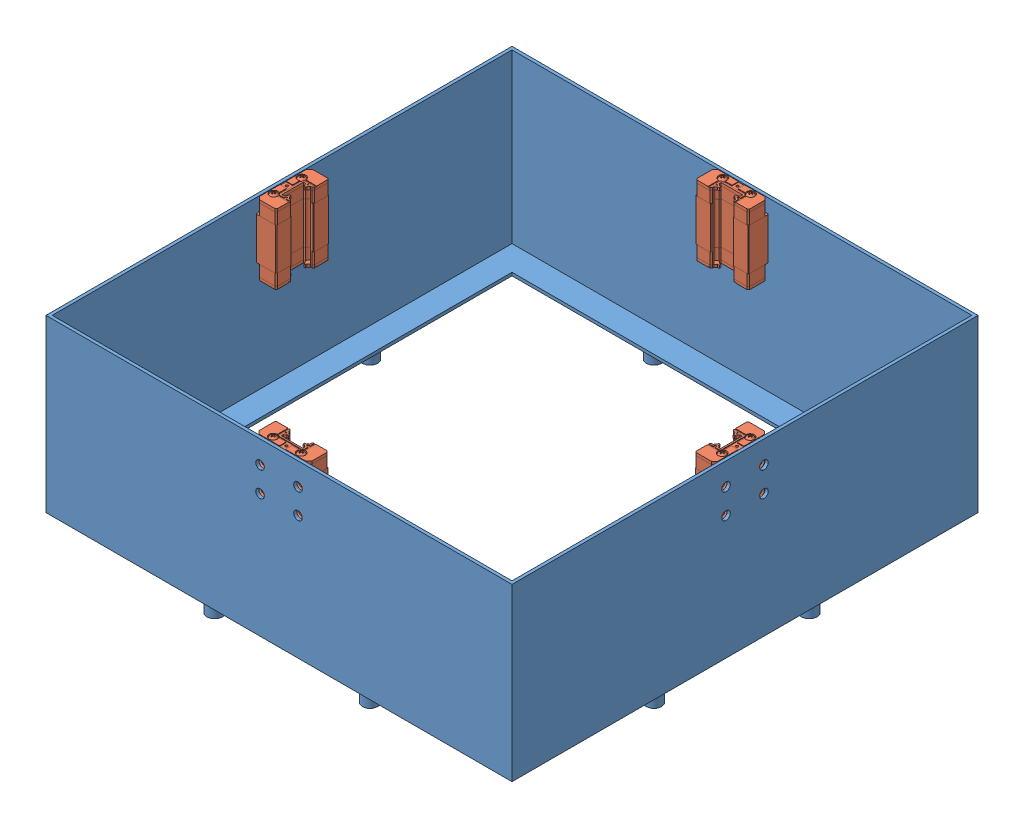
SolidWorks assembly rails boxes, configuration Default. Lengths in mm.
Overall size (150 60.41 150).
5 component instances, 2 part files, 12 mates.
Components (placement in the parent):
- rails-1: rails [Default] at (22.0962 113.7843 129.2829) size (150 60 150)
- MGN7C-1: MGN7C [MGN7C] at (21.9962 102.5343 200.0329) x (-1 0 0) z (0 1 0) size (17 6.5 23.31)
- MGN7C-2: MGN7C [MGN7C] at (-48.6538 102.5343 129.1829) x (0 0 1) z (0 -1 0) size (17 6.5 23.31)
- MGN7C-3: MGN7C [MGN7C] at (92.8462 102.5343 129.3829) x (0 0 -1) z (0 -1 0) size (17 6.5 23.31)
- MGN7C-4: MGN7C [MGN7C] at (22.1962 102.5343 58.5329) x (1 0 0) z (0 1 0) size (17 6.5 23.31)
Mates (geometry in assembly coordinates):
- Concentric3: concentric aligned: circle of rails-1; circle of MGN7C-2
- Concentric5: concentric anti-aligned: circle of rails-1; circle of MGN7C-1
- Coincident19: coincident anti-aligned: plane of rails-1 through (-51.9038 59.7843 203.2829) normal (1 0 0); plane of MGN7C-2 through (-51.9038 95.7843 129.1829) normal (-1 0 0)
- Parallel3: parallel aligned: line of rails-1 through (-51.9038 113.7843 55.2829) axis (0 0 1); line of MGN7C-2 through (-51.7038 113.7843 130.1454) axis (0 0 1)
- Concentric7: concentric anti-aligned: circle of rails-1; circle of MGN7C-4
- Coincident22: coincident anti-aligned: plane of rails-1 through (-51.9038 59.7843 55.2829) normal (0 0 1); plane of MGN7C-4 through (22.1962 109.2843 55.2829) normal (0 0 -1)
- Parallel4: parallel anti-aligned: line of rails-1 through (96.0962 113.7843 55.2829) axis (-1 0 0); line of MGN7C-4 through (14.6962 113.7843 55.4829) axis (1 0 0)
- Coincident25: coincident anti-aligned: plane of rails-1 through (-51.9038 59.7843 203.2829) normal (0 0 -1); plane of MGN7C-1 through (21.9962 109.2843 203.2829) normal (0 0 1)
- Parallel5: parallel anti-aligned: line of rails-1 through (-51.9038 113.7843 203.2829) axis (1 0 0); line of MGN7C-1 through (29.4962 113.7843 203.0829) axis (-1 0 0)
- Concentric8: concentric aligned: circle of rails-1; circle of MGN7C-3
- Coincident30: coincident anti-aligned: plane of rails-1 through (96.0962 59.7843 203.2829) normal (-1 0 0); plane of MGN7C-3 through (96.0962 95.7843 129.3829) normal (1 0 0)
- Parallel6: parallel aligned: line of rails-1 through (96.0962 113.7843 203.2829) axis (0 0 -1); line of MGN7C-3 through (95.8962 113.7843 128.4203) axis (0 0 -1)
